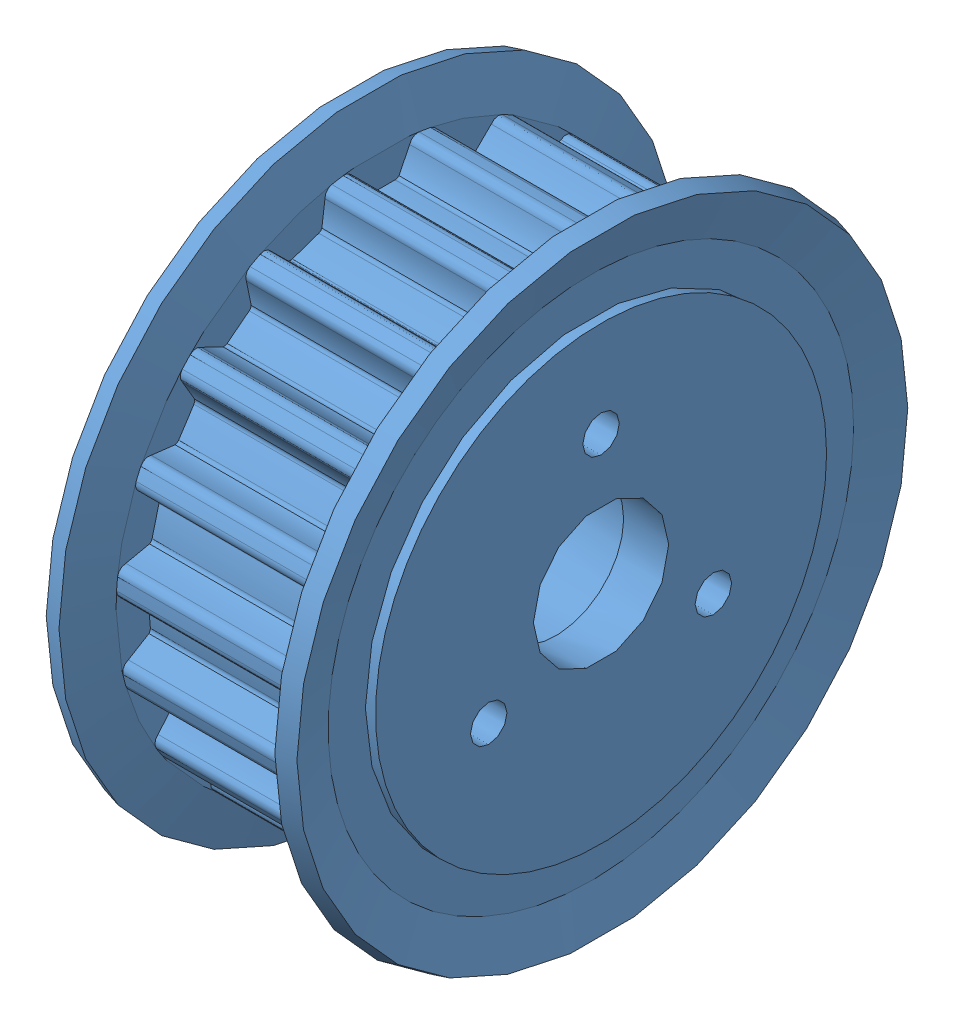
SolidWorks assembly E-HTLA19S8M150-F-12, configuration Default. Lengths in mm.
Overall size (22.51 55.01 55.01).
2 component instances, 2 part files, 0 mates.
Components (placement in the parent):
- E-HTLA19S8M150-F-12_b-1: E-HTLA19S8M150-F-12_b [Default] at origin size (22.51 55.01 55.01)
- 12_SH--1: 12_SH- [Default] at (5 0 0) (suppressed, hidden)
